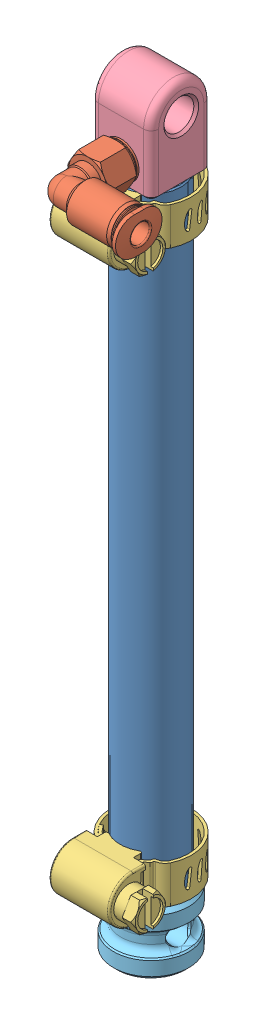
SolidWorks assembly AARL_QR_PN_PA_FL_SH_FL-Flexor, configuration Default. Lengths in mm.
Overall size (24.22 161.92 31.28).
6 component instances, 5 part files, 15 mates.
Components (placement in the parent):
- AARL_QR_PN_PA_FL_SH_FL_001-1: AARL_QR_PN_PA_FL_SH_FL_001 [Resting] at origin size (12.7 130.18 12.7)
- AARL_Puppy_18_02_57_010-QSML-M3-4-1: AARL_Puppy_18_02_57_010-QSML-M3-4 [Default] at (0 69.85 17.85) x (1 0 0) z (0 0 -1) size (20.32 8 18.9)
- AARL_Puppy_18_02_57_011-5388K140_Hose-Clamp-1: AARL_Puppy_18_02_57_011-5388K140_Hose-Clamp [5388K14] at (0 60.1345 0) x (1 0 0) z (0 -1 0) size (19.43 23.71 9.91)
- AARL_Puppy_18_02_57_011-5388K140_Hose-Clamp-2: AARL_Puppy_18_02_57_011-5388K140_Hose-Clamp [5388K14] at (0 -60.1345 0) x (1 0 0) z (0 -1 0) size (19.43 23.71 9.91)
- AARL_QR_PN_EP_001-1: AARL_QR_PN_EP_001 [Default] at (0 77.7875 0) x (0 0 1) z (-1 0 0) size (12.7 31.75 12.7)
- AARL_QR_PN_EP_002-1: AARL_QR_PN_EP_002 [Default] at (0 -65.0875 0) x (-1 0 0) z (0 0 1) size (15.88 25.4 15.88)
Mates (geometry in assembly coordinates):
- Concentric1: concentric aligned: cylinder of AARL_QR_PN_PA_FL_SH_FL_001-1 through (0 11.6086 0) axis (0 1 0) radius 4.7625; cylinder of AARL_QR_PN_EP_001-1 through (0 87.3315 0) axis (0 1 0) radius 4.3656
- Parallel1: parallel aligned: plane of AARL_QR_PN_EP_001-1 through (-6.35 65.0875 6.35) normal (0 0 1)
- Coincident2: coincident anti-aligned: plane of AARL_QR_PN_PA_FL_SH_FL_001-1 through (4.7625 65.0875 0) normal (0 1 0); plane of AARL_QR_PN_EP_001-1 through (-6.35 65.0875 -6.35) normal (0 -1 0)
- Concentric2: concentric aligned: cylinder of AARL_Puppy_18_02_57_010-QSML-M3-4-1 through (0 69.85 6.35) axis (0 0 1) radius 1.5; cylinder of AARL_QR_PN_EP_001-1 through (0 69.85 6.35) axis (0 0 1) radius 2.0193
- Parallel2: parallel anti-aligned: plane of AARL_Puppy_18_02_57_010-QSML-M3-4-1 through (-2.3094 73.85 13.4056) normal (0 1 0); plane of AARL_QR_PN_EP_001-1 through (-6.35 65.0875 -6.35) normal (0 -1 0)
- Coincident4: coincident anti-aligned: plane of AARL_Puppy_18_02_57_010-QSML-M3-4-1 through (0 69.85 6.35) normal (0 0 -1); plane of AARL_QR_PN_EP_001-1 through (-6.35 65.0875 6.35) normal (0 0 1)
- Concentric3: concentric anti-aligned: cylinder of AARL_QR_PN_PA_FL_SH_FL_001-1 through (0 11.6086 0) axis (0 1 0) radius 4.7625; cylinder of AARL_QR_PN_EP_002-1 through (0 -72.8252 0) axis (0 -1 0) radius 4.3656
- Coincident5: coincident anti-aligned: plane of AARL_QR_PN_PA_FL_SH_FL_001-1 through (6.35 -65.0875 0) normal (0 -1 0); plane of AARL_QR_PN_EP_002-1 through (-4.3656 -65.0875 0) normal (0 1 0)
- Parallel3: parallel anti-aligned: cylinder of AARL_QR_PN_EP_001-1 through (-6.35 77.7875 0) axis (1 0 0) radius 3.175; cylinder of AARL_QR_PN_EP_002-1 through (7.9375 -71.4375 0) axis (-1 0 0) radius 2.3813
- Concentric5: concentric aligned: cylinder of AARL_QR_PN_PA_FL_SH_FL_001-1 through (0 11.6086 0) axis (0 1 0) radius 6.35; cylinder of AARL_Puppy_18_02_57_011-5388K140_Hose-Clamp-1 through (0 56.1658 0) axis (0 1 0) radius 7.9375
- Coincident6: coincident aligned: plane of AARL_Puppy_18_02_57_011-5388K140_Hose-Clamp-1 through (6.35 60.1345 10.2337) normal (1 0 0); plane of AARL_QR_PN_EP_001-1 through (6.35 77.7875 0) normal (1 0 0)
- Coincident7: coincident anti-aligned: plane of AARL_Puppy_18_02_57_011-5388K140_Hose-Clamp-1 through (0 65.0875 0) normal (0 1 0); plane of AARL_QR_PN_EP_001-1 through (-6.35 65.0875 -6.35) normal (0 -1 0)
- Concentric6: concentric aligned: cylinder of AARL_QR_PN_PA_FL_SH_FL_001-1 through (0 11.6086 0) axis (0 1 0) radius 6.35; cylinder of AARL_Puppy_18_02_57_011-5388K140_Hose-Clamp-2 through (0 -64.1033 0) axis (0 1 0) radius 7.9375
- Coincident8: coincident aligned: plane of AARL_Puppy_18_02_57_011-5388K140_Hose-Clamp-1 through (6.35 60.1345 10.2337) normal (1 0 0); plane of AARL_Puppy_18_02_57_011-5388K140_Hose-Clamp-2 through (6.35 -60.1345 10.2337) normal (1 0 0)
- Coincident9: coincident anti-aligned: plane of AARL_Puppy_18_02_57_011-5388K140_Hose-Clamp-2 through (0 -65.0875 0) normal (0 -1 0); plane of AARL_QR_PN_EP_002-1 through (-4.3656 -65.0875 0) normal (0 1 0)
